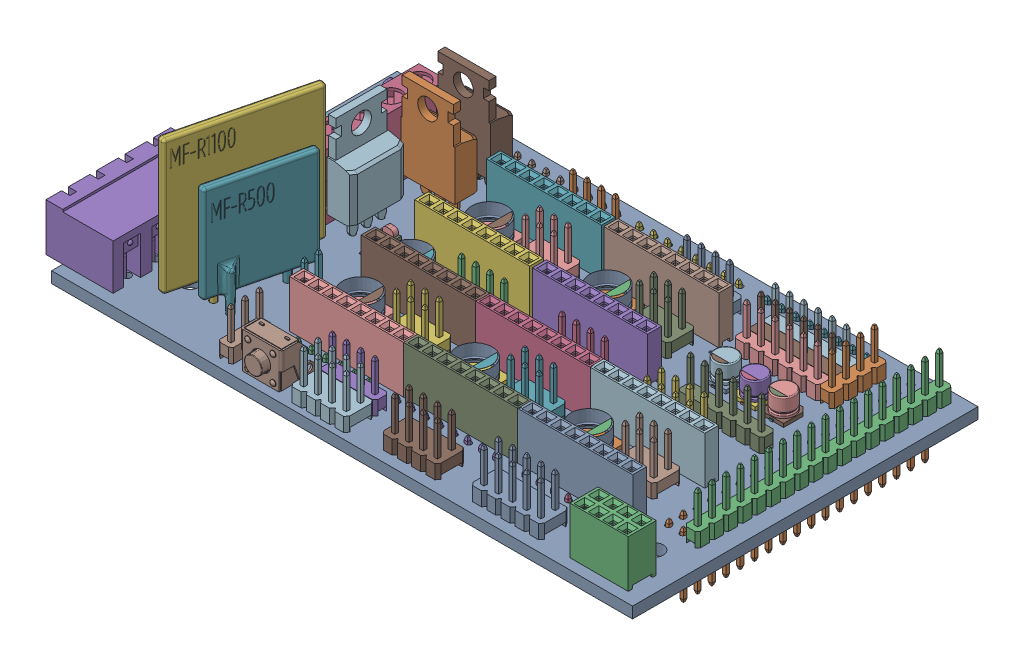
SolidWorks assembly RAMPS1_4, configuration По умолчанию. Lengths in mm.
Overall size (106.85 37.63 61.76).
107 component instances, 31 part files, 0 mates.
Components (placement in the parent):
- RAMPS1_4_1-1: RAMPS1_4_1 [По умолчанию] at (-38.4421 2.2803 -26.502) x (1 0 0) z (0 1 0) size (103.85 61.76 2)
- User Library-POWER MOSFET, NON-SURFACE-MOUNT-1: User Library-POWER MOSFET, NON-SURFACE-MOUNT [По умолчанию] at (-31.1839 8.1208 -13.4695) x (-1 0 0) z (0 -1 0) size (9.65 4.5 28.38)
- female_header_a-bl254-dg-g08d-1: female_header_a-bl254-dg-g08d [По умолчанию] at (41.0483 4.2583 25.6311) size (10.41 11.65 5)
- female_header_a-bl254-eg-g08d-1: female_header_a-bl254-eg-g08d [По умолчанию] at (6.4047 4.2963 4.0858) size (20.57 11.65 2.5)
- female_header_a-bl254-eg-g08d-2: female_header_a-bl254-eg-g08d [По умолчанию] at (6.3863 4.2963 -6.1397) size (20.57 11.65 2.5)
- female_header_a-bl254-eg-g08d-3: female_header_a-bl254-eg-g08d [По умолчанию] at (-14.6923 4.2963 -6.1397) size (20.57 11.65 2.5)
- female_header_a-bl254-eg-g08d-4: female_header_a-bl254-eg-g08d [По умолчанию] at (-14.6047 4.2963 -18.9127) size (20.57 11.65 2.5)
- female_header_a-bl254-eg-g08d-5: female_header_a-bl254-eg-g08d [По умолчанию] at (6.3793 4.2963 -18.9127) size (20.57 11.65 2.5)
- female_header_a-bl254-eg-g08d-6: female_header_a-bl254-eg-g08d [По умолчанию] at (6.414 4.2963 16.9123) size (20.57 11.65 2.5)
- female_header_a-bl254-eg-g08d-7: female_header_a-bl254-eg-g08d [По умолчанию] at (-13.9941 4.2963 16.9123) size (20.57 11.65 2.5)
- female_header_a-bl254-eg-g08d-8: female_header_a-bl254-eg-g08d [По умолчанию] at (-14.0103 4.2963 4.0799) size (20.57 11.65 2.5)
- female_header_a-bl254-eg-g08d-9: female_header_a-bl254-eg-g08d [По умолчанию] at (26.8453 4.2963 4.0799) size (20.57 11.65 2.5)
- female_header_a-bl254-eg-g08d-10: female_header_a-bl254-eg-g08d [По умолчанию] at (26.8273 4.2963 16.9325) size (20.57 11.65 2.5)
- pin_header_aw254-dg-g36d-1: pin_header_aw254-dg-g36d [По умолчанию] at (40.9113 2.2243 -7.3898) x (0 0 1) z (-1 0 0) size (45.72 11.5 5.08)
- pin_header_aw140-eg-g18d-1: pin_header_aw140-eg-g18d [По умолчанию] at (44.7503 4.3173 -7.3949) x (0 0 -1) z (-1 0 0) size (45.62 11.2 2.5)
- pin_header_aw140-eg-g08d-1: pin_header_aw140-eg-g08d [По умолчанию] at (28.1033 2.2803 19.4616) size (20.22 11.2 2.5)
- pin_header_aw140-eg-g08d-2: pin_header_aw140-eg-g08d [По умолчанию] at (5.0609 2.2803 19.4616) size (20.22 11.2 2.5)
- pin_header_aw140-eg-g08d-3: pin_header_aw140-eg-g08d [По умолчанию] at (-0.0426 2.2803 -29.0108) size (20.22 11.2 2.5)
- pin_header_aw140-eg-g08d-4: pin_header_aw140-eg-g08d [По умолчанию] at (22.8713 2.2803 -29.0108) size (20.22 11.2 2.5)
- pin_header_aw140-eg-g08d-5: pin_header_aw140-eg-g08d [По умолчанию] at (-21.773 2.2803 -29.0108) size (20.22 11.2 2.5)
- pin_header_aw140-eg-g06d-1: pin_header_aw140-eg-g06d [По умолчанию] at (29.4382 4.2803 -6.1813) x (-1 0 0) z (0 0 1) size (15.14 11.2 2.5)
- pin_header_aw140-eg-g06d-2: pin_header_aw140-eg-g06d [По умолчанию] at (26.2798 4.2623 -19.3796) x (-1 0 0) z (0 0 1) size (15.14 11.2 2.5)
- pin_header_aw140-eg-g06d-3: pin_header_aw140-eg-g06d [По умолчанию] at (26.2798 4.2623 -21.9464) x (-1 0 0) z (0 0 1) size (15.14 11.2 2.5)
- pin_header_aw140-eg-g06d-4: pin_header_aw140-eg-g06d [По умолчанию] at (26.2798 4.2623 -24.4908) x (-1 0 0) z (0 0 1) size (15.14 11.2 2.5)
- pin_header_aw140-eg-g04d-1: pin_header_aw140-eg-g04d [По умолчанию] at (8.4073 4.2803 -24.0519) x (-1 0 0) z (0 0 1) size (10.06 11.2 2.5)
- pin_header_aw140-eg-g04d-2: pin_header_aw140-eg-g04d [По умолчанию] at (-12.021 4.2623 -24.0519) x (-1 0 0) z (0 0 1) size (10.06 11.2 2.5)
- pin_header_aw140-eg-g04d-3: pin_header_aw140-eg-g04d [По умолчанию] at (-8.9039 4.2623 -1.0355) x (-1 0 0) z (0 0 1) size (10.06 11.2 2.5)
- pin_header_aw140-eg-g04d-4: pin_header_aw140-eg-g04d [По умолчанию] at (9.0685 4.2623 -1.0355) x (-1 0 0) z (0 0 1) size (10.06 11.2 2.5)
- pin_header_aw140-eg-g04d-5: pin_header_aw140-eg-g04d [По умолчанию] at (-8.3709 4.2803 22.5944) x (-1 0 0) z (0 0 1) size (10.06 11.2 2.5)
- pin_header_aw254-dg-g06d-1: pin_header_aw254-dg-g06d [По умолчанию] at (-10.2573 4.2803 9.2323) x (-1 0 0) z (0 0 1) size (7.62 11.5 5.08)
- pin_header_aw254-dg-g06d-2: pin_header_aw254-dg-g06d [По умолчанию] at (10.1683 4.2623 9.2323) x (-1 0 0) z (0 0 1) size (7.62 11.5 5.08)
- pin_header_aw254-dg-g06d-3: pin_header_aw254-dg-g06d [По умолчанию] at (30.6527 4.2623 9.2323) x (-1 0 0) z (0 0 1) size (7.62 11.5 5.08)
- pin_header_aw254-dg-g06d-4: pin_header_aw254-dg-g06d [По умолчанию] at (10.1683 4.2623 -13.7827) x (-1 0 0) z (0 0 1) size (7.62 11.5 5.08)
- pin_header_aw254-dg-g06d-5: pin_header_aw254-dg-g06d [По умолчанию] at (-10.2204 4.2623 -13.7827) x (-1 0 0) z (0 0 1) size (7.62 11.5 5.08)
- pin_header_aw254-dg-g08d-1: pin_header_aw254-dg-g08d [По умолчанию] at (7.0775 4.2803 25.6017) x (-1 0 0) z (0 0 1) size (10.16 11.5 5.08)
- pin_header_aw254-dg-g08d-2: pin_header_aw254-dg-g08d [По умолчанию] at (-8.3884 4.2803 26.4286) x (-1 0 0) z (0 0 1) size (10.16 11.5 5.08)
- pin_header_aw254-dg-g10d-1: pin_header_aw254-dg-g10d [По умолчанию] at (24.3252 4.2803 25.6162) x (-1 0 0) z (0 0 1) size (12.7 11.5 5.08)
- pin_header_aw140-eg-g04d-6: pin_header_aw140-eg-g04d [По умолчанию] at (35.1498 4.2623 -23.186) x (0 0 -1) z (-1 0 0) size (10.06 11.2 2.5)
- pin_header_aw140-eg-g06d-5: pin_header_aw140-eg-g06d [По умолчанию] at (-15.2568 2.2803 19.3514) size (15.14 11.2 2.5)
- terminal_blocks_a-tb500-to06-1: terminal_blocks_a-tb500-to06 [По умолчанию] at (-37.5276 4.2805 -9.866) x (0 0 1) z (-1 0 0) size (30.6 13.8 8.3)
- terminal_blocks_a-tb508-oq04ch-1: terminal_blocks_a-tb508-oq04ch [По умолчанию] at (-57.9426 4.2803 17.0267) x (0 0 1) z (-1 0 0) size (22.32 12.5 12)
- pin_header_aw254-dg-g08d-3: pin_header_aw254-dg-g08d [По умолчанию] at (26.8817 4.262 0.2918) x (-1 0 0) z (0 0 1) size (10.16 11.5 5.08)
- pin_header_aw140-eg-g02d-1: pin_header_aw140-eg-g02d [По умолчанию] at (-26.0896 4.2803 12.3888) x (0 0 1) z (1 0 0) size (4.98 11.2 2.5)
- pin_header_aw140-eg-g03d-1: pin_header_aw140-eg-g03d [По умолчанию] at (-25.5036 4.2803 24.8649) x (0 0 1) z (1 0 0) size (7.52 11.2 2.5)
- User Library-CAPSMD6_3x3_9-1: User Library-CAPSMD6_3x3_9 [По умолчанию] at (-23.4034 4.2803 -13.8521) x (0 0 -1) z (0 1 0) size (6.6 7 3.91)
  - User Library-CAPSMD6_3x3_9_CAP003-1: User Library-CAPSMD6_3x3_9_CAP003 [По умолчанию] at origin size (0.65 2.6 0.32)
  - User Library-CAPSMD6_3x3_9_CAP-1: User Library-CAPSMD6_3x3_9_CAP [По умолчанию] at origin size (6.3 6.3 3.06)
  - User Library-CAPSMD6_3x3_9_CAP001-1: User Library-CAPSMD6_3x3_9_CAP001 [По умолчанию] at origin size (6.6 6.6 0.64)
  - User Library-CAPSMD6_3x3_9_CAP002-1: User Library-CAPSMD6_3x3_9_CAP002 [По умолчанию] at origin size (5.11 1.47 0.01)
  - User Library-CAPSMD6_3x3_9_CAP004-1: User Library-CAPSMD6_3x3_9_CAP004 [По умолчанию] at origin size (0.65 2.6 0.32)
- User Library-CAPSMD6_3x3_9-2: User Library-CAPSMD6_3x3_9 [По умолчанию] at (-2.2688 4.2803 -13.8521) x (0 0 -1) z (0 1 0) size (6.6 7 3.91)
  - User Library-CAPSMD6_3x3_9_CAP003-1: User Library-CAPSMD6_3x3_9_CAP003 [По умолчанию] at origin size (0.65 2.6 0.32)
  - User Library-CAPSMD6_3x3_9_CAP-1: User Library-CAPSMD6_3x3_9_CAP [По умолчанию] at origin size (6.3 6.3 3.06)
  - User Library-CAPSMD6_3x3_9_CAP001-1: User Library-CAPSMD6_3x3_9_CAP001 [По умолчанию] at origin size (6.6 6.6 0.64)
  - User Library-CAPSMD6_3x3_9_CAP002-1: User Library-CAPSMD6_3x3_9_CAP002 [По умолчанию] at origin size (5.11 1.47 0.01)
  - User Library-CAPSMD6_3x3_9_CAP004-1: User Library-CAPSMD6_3x3_9_CAP004 [По умолчанию] at origin size (0.65 2.6 0.32)
- User Library-CAPSMD6_3x3_9-3: User Library-CAPSMD6_3x3_9 [По умолчанию] at (-2.8787 4.2803 9.2865) x (0 0 -1) z (0 1 0) size (6.6 7 3.91)
  - User Library-CAPSMD6_3x3_9_CAP003-1: User Library-CAPSMD6_3x3_9_CAP003 [По умолчанию] at origin size (0.65 2.6 0.32)
  - User Library-CAPSMD6_3x3_9_CAP-1: User Library-CAPSMD6_3x3_9_CAP [По умолчанию] at origin size (6.3 6.3 3.06)
  - User Library-CAPSMD6_3x3_9_CAP001-1: User Library-CAPSMD6_3x3_9_CAP001 [По умолчанию] at origin size (6.6 6.6 0.64)
  - User Library-CAPSMD6_3x3_9_CAP002-1: User Library-CAPSMD6_3x3_9_CAP002 [По умолчанию] at origin size (5.11 1.47 0.01)
  - User Library-CAPSMD6_3x3_9_CAP004-1: User Library-CAPSMD6_3x3_9_CAP004 [По умолчанию] at origin size (0.65 2.6 0.32)
- User Library-CAPSMD6_3x3_9-4: User Library-CAPSMD6_3x3_9 [По умолчанию] at (-23.2996 4.2803 9.2865) x (0 0 -1) z (0 1 0) size (6.6 7 3.91)
  - User Library-CAPSMD6_3x3_9_CAP003-1: User Library-CAPSMD6_3x3_9_CAP003 [По умолчанию] at origin size (0.65 2.6 0.32)
  - User Library-CAPSMD6_3x3_9_CAP-1: User Library-CAPSMD6_3x3_9_CAP [По умолчанию] at origin size (6.3 6.3 3.06)
  - User Library-CAPSMD6_3x3_9_CAP001-1: User Library-CAPSMD6_3x3_9_CAP001 [По умолчанию] at origin size (6.6 6.6 0.64)
  - User Library-CAPSMD6_3x3_9_CAP002-1: User Library-CAPSMD6_3x3_9_CAP002 [По умолчанию] at origin size (5.11 1.47 0.01)
  - User Library-CAPSMD6_3x3_9_CAP004-1: User Library-CAPSMD6_3x3_9_CAP004 [По умолчанию] at origin size (0.65 2.6 0.32)
- User Library-CAPSMD6_3x3_9-5: User Library-CAPSMD6_3x3_9 [По умолчанию] at (17.5196 4.2803 9.2865) x (0 0 -1) z (0 1 0) size (6.6 7 3.91)
  - User Library-CAPSMD6_3x3_9_CAP003-1: User Library-CAPSMD6_3x3_9_CAP003 [По умолчанию] at origin size (0.65 2.6 0.32)
  - User Library-CAPSMD6_3x3_9_CAP-1: User Library-CAPSMD6_3x3_9_CAP [По умолчанию] at origin size (6.3 6.3 3.06)
  - User Library-CAPSMD6_3x3_9_CAP001-1: User Library-CAPSMD6_3x3_9_CAP001 [По умолчанию] at origin size (6.6 6.6 0.64)
  - User Library-CAPSMD6_3x3_9_CAP002-1: User Library-CAPSMD6_3x3_9_CAP002 [По умолчанию] at origin size (5.11 1.47 0.01)
  - User Library-CAPSMD6_3x3_9_CAP004-1: User Library-CAPSMD6_3x3_9_CAP004 [По умолчанию] at origin size (0.65 2.6 0.32)
- User Library-CAPSMD6_3x3_9-6: User Library-CAPSMD6_3x3_9 [По умолчанию] at (-24.6073 4.2803 -1.0117) x (0 0 -1) z (0 1 0) size (6.6 7 3.91)
  - User Library-CAPSMD6_3x3_9_CAP003-1: User Library-CAPSMD6_3x3_9_CAP003 [По умолчанию] at origin size (0.65 2.6 0.32)
  - User Library-CAPSMD6_3x3_9_CAP-1: User Library-CAPSMD6_3x3_9_CAP [По умолчанию] at origin size (6.3 6.3 3.06)
  - User Library-CAPSMD6_3x3_9_CAP001-1: User Library-CAPSMD6_3x3_9_CAP001 [По умолчанию] at origin size (6.6 6.6 0.64)
  - User Library-CAPSMD6_3x3_9_CAP002-1: User Library-CAPSMD6_3x3_9_CAP002 [По умолчанию] at origin size (5.11 1.47 0.01)
  - User Library-CAPSMD6_3x3_9_CAP004-1: User Library-CAPSMD6_3x3_9_CAP004 [По умолчанию] at origin size (0.65 2.6 0.32)
- User Library-CAPSMD4x3_9-1: User Library-CAPSMD4x3_9 [По умолчанию] at (22.2937 4.2803 -15.1178) x (1 0 0) z (0 1 0) size (4.3 4.6 3.91)
  - User Library-CAPSMD4x3_9_CAPSMD4x3_9003-1: User Library-CAPSMD4x3_9_CAPSMD4x3_9003 [По умолчанию] at origin size (0.65 1.8 0.32)
  - User Library-CAPSMD4x3_9_CAPSMD4x3_9004-1: User Library-CAPSMD4x3_9_CAPSMD4x3_9004 [По умолчанию] at origin size (0.65 1.8 0.32)
  - User Library-CAPSMD4x3_9_CAPSMD4x3_9002-1: User Library-CAPSMD4x3_9_CAPSMD4x3_9002 [По умолчанию] at origin size (3.12 0.9 0.01)
  - User Library-CAPSMD4x3_9_CAPSMD4x3_9001-1: User Library-CAPSMD4x3_9_CAPSMD4x3_9001 [По умолчанию] at origin size (4 4 3.27)
  - User Library-CAPSMD4x3_9_CAPSMD4x3_9-1: User Library-CAPSMD4x3_9_CAPSMD4x3_9 [По умолчанию] at origin size (4.3 4.3 0.64)
- User Library-CAPSMD4x3_9-2: User Library-CAPSMD4x3_9 [По умолчанию] at (27.5508 4.2803 -15.1178) x (1 0 0) z (0 1 0) size (4.3 4.6 3.91)
  - User Library-CAPSMD4x3_9_CAPSMD4x3_9003-1: User Library-CAPSMD4x3_9_CAPSMD4x3_9003 [По умолчанию] at origin size (0.65 1.8 0.32)
  - User Library-CAPSMD4x3_9_CAPSMD4x3_9004-1: User Library-CAPSMD4x3_9_CAPSMD4x3_9004 [По умолчанию] at origin size (0.65 1.8 0.32)
  - User Library-CAPSMD4x3_9_CAPSMD4x3_9002-1: User Library-CAPSMD4x3_9_CAPSMD4x3_9002 [По умолчанию] at origin size (3.12 0.9 0.01)
  - User Library-CAPSMD4x3_9_CAPSMD4x3_9001-1: User Library-CAPSMD4x3_9_CAPSMD4x3_9001 [По умолчанию] at origin size (4 4 3.27)
  - User Library-CAPSMD4x3_9_CAPSMD4x3_9-1: User Library-CAPSMD4x3_9_CAPSMD4x3_9 [По умолчанию] at origin size (4.3 4.3 0.64)
- User Library-CAPSMD4x3_9-3: User Library-CAPSMD4x3_9 [По умолчанию] at (32.6212 4.2803 -15.1178) x (1 0 0) z (0 1 0) size (4.3 4.6 3.91)
  - User Library-CAPSMD4x3_9_CAPSMD4x3_9003-1: User Library-CAPSMD4x3_9_CAPSMD4x3_9003 [По умолчанию] at origin size (0.65 1.8 0.32)
  - User Library-CAPSMD4x3_9_CAPSMD4x3_9004-1: User Library-CAPSMD4x3_9_CAPSMD4x3_9004 [По умолчанию] at origin size (0.65 1.8 0.32)
  - User Library-CAPSMD4x3_9_CAPSMD4x3_9002-1: User Library-CAPSMD4x3_9_CAPSMD4x3_9002 [По умолчанию] at origin size (3.12 0.9 0.01)
  - User Library-CAPSMD4x3_9_CAPSMD4x3_9001-1: User Library-CAPSMD4x3_9_CAPSMD4x3_9001 [По умолчанию] at origin size (4 4 3.27)
  - User Library-CAPSMD4x3_9_CAPSMD4x3_9-1: User Library-CAPSMD4x3_9_CAPSMD4x3_9 [По умолчанию] at origin size (4.3 4.3 0.64)
- User Library-APA3010GCCK_GREEN-1: User Library-APA3010GCCK_GREEN [По умолчанию] at (-34.2243 4.3303 -27.7242) x (0 0 1) z (-1 0 0) size (3 2 1)
- User Library-APA3010GCCK_RED-1: User Library-APA3010GCCK_RED [По умолчанию] at (-49.6186 4.3303 -27.7242) x (0 0 1) z (-1 0 0) size (3 2 1)
- User Library-APA3010GCCK_RED-2: User Library-APA3010GCCK_RED [По умолчанию] at (-52.1606 4.3303 -27.7242) x (0 0 1) z (-1 0 0) size (3 2 1)
- User Library-MF-R1100___ _________-1: User Library-MF-R1100___ _________ [По умолчанию] at (-35.8426 -0.3427 15.082) x (0 0 -1) z (0 -1 0) size (23.64 7.06 35.7)
- User Library-MF-R500___ _________-1: User Library-MF-R500___ _________ [По умолчанию] at (-32.3357 -0.5897 15.5605) x (0.000533 0 -1) z (0 -1 0) size (17.04 5.43 29.1)
- User Library-SWITCH, TACTILE, RIGHT ANGLE, 12VDC, 50MA, 6_85MM ACTUAT_OR, WEALTH METAL TC-0244Z-1: User Library-SWITCH, TACTILE, RIGHT ANGLE, 12VDC, 50MA, 6_85MM ACTUAT_OR, WEALTH METAL TC-0244Z [По умолчанию] at (-19.0613 3.9803 23.5512) size (7.4 11 8)
- User Library-APA3010GCCK_RED-3: User Library-APA3010GCCK_RED [По умолчанию] at (-29.5185 4.3303 -5.1301) size (3 2 1)
- User Library-POWER MOSFET, NON-SURFACE-MOUNT-2: User Library-POWER MOSFET, NON-SURFACE-MOUNT [По умолчанию] at (-31.3941 8.4328 -20.0341) x (-1 0 0) z (0 -1 0) size (9.65 4.5 28.38)
- User Library-POWER MOSFET, NON-SURFACE-MOUNT-3: User Library-POWER MOSFET, NON-SURFACE-MOUNT [По умолчанию] at (-36.1067 8.2818 -5.2135) x (0 0 -1) z (0 -1 0) size (9.65 4.5 28.38)
